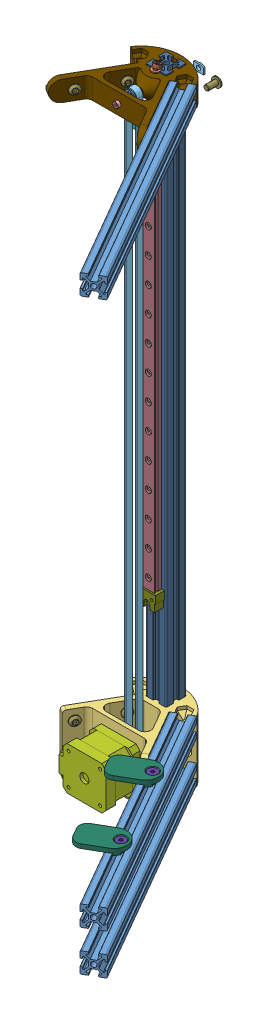
SolidWorks assembly Kossel ass-01, configuration Default. Lengths in mm.
Overall size (201.64 606.12 243.34).
97 component instances, 23 part files, 0 mates.
Components (placement in the parent):
- F623ZZ-1: F623ZZ [Default] at (0 -11 32.1273) x (-0.566355 0.824161 0) z (-0.824161 -0.566355 0) size (11.5 4 11.5)
- m3 t-slot-1: m3 t-slot [Default] at (0 -155.5 6.8) size (10 5 2.2)
- M3x8 socket screw-1: M3x8 socket screw [Default] at (0 -330.5 5) x (1 0 0) z (0 -1 0) size (5.6 10.9 5.6)
- m4 nut-1: m4 nut [Default] at (0 -16.4689 14.8541) x (0.866025 -0.154508 -0.475528) z (0.5 0.267617 0.823639) size (8.08 3 7)
- m5 t-slot-1: m5 t-slot [Default] at (41.8929 -590 51.6366) x (0 1 0) z (-0.866025 0 0.5) size (10 7 2.5)
- OMRON-SS-1: OMRON-SS [Default] at (-4.75 -39.5 22.2) x (-1 0 0) z (0 0 1) size (19.8 15.06 6.4)
- m3 t-slot-2: m3 t-slot [Default] at (0 -380.5 6.8) size (10 5 2.2)
- m3 t-slot-3: m3 t-slot [Default] at (0 -205.5 6.8) size (10 5 2.2)
- M3x8 socket screw-2: M3x8 socket screw [Default] at (0 -405.5 5) x (1 0 0) z (0 -1 0) size (5.6 10.9 5.6)
- m5 t-slot-2: m5 t-slot [Default] at (41.8929 -11 51.6367) x (0 1 0) z (-0.866025 0 0.5) size (10 7 2.5)
- m5 t-slot-3: m5 t-slot [Default] at (22.8929 -590 18.7277) x (0 -1 0) z (-0.866025 0 0.5) size (10 7 2.5)
- MP1872-Stepper_Motor_NEMA17-1: MP1872-Stepper_Motor_NEMA17 [Default] at (0.2889 -570 63.8273) x (0 1 0) z (-1 0 0) size (42.3 53.75 48.3)
- m3 nut-1: m3 nut [Default] at (0 -11 26.1273) size (5.77 5 2)
- Kossel-parts001-1: Kossel-parts001 [Default] at (0.2889 -570 36.5273) x (-0.148937 0.988847 0) z (0 0 1) size (14.7 14.7 12)
- m3 t-slot-4: m3 t-slot [Default] at (0 -405.5 6.8) size (10 5 2.2)
- M3x8 socket screw-3: M3x8 socket screw [Default] at (0 -255.5 5) x (1 0 0) z (0 -1 0) size (5.6 10.9 5.6)
- m5 t-slot-4: m5 t-slot [Default] at (22.8929 -11 18.7277) x (0 -1 0) z (-0.866025 0 0.5) size (10 7 2.5)
- m5 t-slot-5: m5 t-slot [Default] at (-41.8929 -590 51.6366) x (0 1 0) z (0.866025 0 0.5) size (10 7 2.5)
- 20x20x600-1: 20x20x600 [Default] x (-1 0 0) z (0 0 1) size (20 600 20)
- m4x20 socket screw-1: m4x20 socket screw [Default] at (0 -18.1808 15.4104) x (-0.866088 -0.154475 -0.475425) z (0.499892 -0.267636 -0.823699) size (7 24 7)
- F623ZZ-2: F623ZZ [Default] at (0 -11 32.1273) x (1 0 0) z (0 -1 0) size (11.5 4 11.5)
- m3 t-slot-5: m3 t-slot [Default] at (0 -330.5 6.8) size (10 5 2.2)
- M3x8 socket screw-4: M3x8 socket screw [Default] at (0 -130.5 5) x (1 0 0) z (0 -1 0) size (5.6 10.9 5.6)
- m5 t-slot-6: m5 t-slot [Default] at (-22.8929 -550 18.7277) x (0 -1 0) z (0.866025 0 0.5) size (10 7 2.5)
- m5 t-slot-7: m5 t-slot [Default] at (41.8929 -550 51.6366) x (0 1 0) z (-0.866025 0 0.5) size (10 7 2.5)
- m5 t-slot-8: m5 t-slot [Default] at (104.3002 -542 148.7294) x (0.866025 0 -0.5) z (0 -1 0) size (10 7 2.5)
- m3 t-slot-6: m3 t-slot [Default] at (0 -355.5 6.8) size (10 5 2.2)
- m5 t-slot-9: m5 t-slot [Default] at (-22.8929 -590 18.7277) x (0 -1 0) z (0.866025 0 0.5) size (10 7 2.5)
- m5x10 button screw-1: m5x10 button screw [Default] at (-42.7585 -11 51.1369) x (0.1551 -0.950671 -0.268642) z (-0.475336 -0.310201 0.823305) size (9.3 12.55 9.3)
- HI_r_SSEBLT13-396-1: HI_r_SSEBLT13-396 [Default] at (0 -45 10) x (1 0 0) z (0 -1 0) size (12 7.5 396)
- m3 t-slot-7: m3 t-slot [Default] at (0 -305.5 6.8) size (10 5 2.2)
- m3 t-slot-8: m3 t-slot [Default] at (0 -55.5 6.8) size (10 5 2.2)
- m5 t-slot-10: m5 t-slot [Default] at (61.6002 -542 74.7708) x (-0.866025 0 0.5) z (0 -1 0) size (10 7 2.5)
- m4x10 socket screw-1: m4x10 socket screw [Default] at (15.7889 -554.5 53.0773) x (0.60127 0.799046 0) z (-0.799046 0.60127 0) size (7 14 7)
- m5 t-slot-11: m5 t-slot [Default] at (-41.8929 -550 51.6366) x (0 -1 0) z (0.866025 0 0.5) size (10 7 2.5)
- m5x10 button screw-2: m5x10 button screw [Default] at (-23.7585 -11 18.2279) x (-0.482212 -0.264357 0.835216) z (-0.132178 0.964425 0.22894) size (9.3 12.55 9.3)
- m3 t-slot-9: m3 t-slot [Default] at (0 -280.5 6.8) size (10 5 2.2)
- M3x8 socket screw-5: M3x8 socket screw [Default] at (0 -205.5 5) x (1 0 0) z (0 -1 0) size (5.6 10.9 5.6)
- M3x8 socket screw-6: M3x8 socket screw [Default] at (0 -80.5 5) x (-0.999964 0.008516 0) z (0.008516 0.999964 0) size (5.6 10.9 5.6)
- glass_tab sw-1: glass_tab sw [Default] at (61.6002 -536 74.7708) x (-0.5 0 -0.866025) z (0 1 0) size (25.4 40.9 6)
- m5 t-slot-12: m5 t-slot [Default] at (22.8929 -550 18.7277) x (0 -1 0) z (-0.866025 0 0.5) size (10 7 2.5)
- m5x10 button screw-3: m5x10 button screw [Default] at (42.7585 -11 51.1369) x (-0.442414 -0.465918 -0.766284) z (-0.232959 0.884828 -0.403497) size (9.3 12.55 9.3)
- m3 t-slot-10: m3 t-slot [Default] at (0 -255.5 6.8) size (10 5 2.2)
- M3x8 socket screw-7: M3x8 socket screw [Default] at (0 -105.5 5) x (1 0 0) z (0 -1 0) size (5.6 10.9 5.6)
- M3x8 socket screw-8: M3x8 socket screw [Default] at (0 -155.5 5) x (1 0 0) z (0 -1 0) size (5.6 10.9 5.6)
- M3x8 socket screw-9: M3x8 socket screw [Default] at (0 -380.5 5) x (0.292877 0.95615 0) z (0.95615 -0.292877 0) size (5.6 10.9 5.6)
- m5 t-slot-13: m5 t-slot [Default] at (11.3303 -8.8222 -20.6644) x (-1 0 0) z (0 0 -1) size (10 7 2.5)
- m5x10 button screw-4: m5x10 button screw [Default] at (23.7585 -11 18.2279) x (-0.078334 0.987651 -0.135679) z (0.493826 0.156669 0.855331) size (9.3 12.55 9.3)
- m3 t-slot-11: m3 t-slot [Default] at (0 -180.5 6.8) size (10 5 2.2)
- M3x8 socket screw-10: M3x8 socket screw [Default] at (0 -451.5 6) x (1 0 0) z (0 -1 0) size (5.6 10.9 5.6)
- endstop sw-1: endstop sw [Default] at (0 -441 19) x (-1 0 0) z (0 0 1) size (17 15 11)
- m4x10 socket screw-2: m4x10 socket screw [Default] at (-15.2111 -554.5 53.0773) x (-0.923728 -0.383049 0) z (0.383049 -0.923728 0) size (7 14 7)
- m5x10 button screw-5: m5x10 button screw [Default] at (30.073 -11 -9.3275) x (0.79504 -0.606557 0) z (0.606557 0.79504 0) size (9.3 12.55 9.3)
- m5x10 button screw-6: m5x10 button screw [Default] at (42.7585 -590 51.1369) x (0.447252 -0.447062 0.774662) z (-0.223531 -0.894503 -0.387167) size (9.3 12.55 9.3)
- M3x8 socket screw-11: M3x8 socket screw [Default] at (0 -355.5 5) x (0.606296 -0.795239 0) z (-0.795239 -0.606296 0) size (5.6 10.9 5.6)
- M5x10 Socket Flat screw-1: M5x10 Socket Flat screw [Default] at (61.6002 -546.6 74.7708) size (9.52 10 9.52)
- m4x10 socket screw-3: m4x10 socket screw [Default] at (-15.2111 -585.5 53.0773) x (1 0 0) z (0 1 0) size (7 14 7)
- m5x10 button screw-7: m5x10 button screw [Default] at (0 -550 -4.5) x (-0.959087 0.28311 0) z (-0.28311 -0.959087 0) size (9.3 12.55 9.3)
- m5x10 button screw-8: m5x10 button screw [Default] at (23.7585 -550 18.2279) x (0.091381 -0.983157 0.158276) z (-0.491579 -0.182762 -0.851439) size (9.3 12.55 9.3)
- frame_top 2020sw-1: frame_top 2020sw [Default] at (0 -11 3.0773) x (-1 0 0) z (0 1 0) size (98.34 87.53 20.11)
- M3x8 socket screw-12: M3x8 socket screw [Default] at (0 -280.5 5) x (1 0 0) z (0 -1 0) size (5.6 10.9 5.6)
- m5x10 button screw-9: m5x10 button screw [Default] at (0 -580 -4.5) x (1 0 0) z (0 1 0) size (9.3 12.55 9.3)
- m5x10 button screw-10: m5x10 button screw [Default] at (23.7585 -590 18.2279) x (0.25 0.866025 0.433013) z (0.433013 -0.5 0.75) size (9.3 12.55 9.3)
- 20x20x240-1: 20x20x240 [Default] at (143.8163 -550 215.1731) x (0.866025 0 -0.5) z (0 1 0) size (20 240 20)
- endstop sw-2: endstop sw [Default] at (0 -45 19) size (17 15 11)
- m5 t-slot-14: m5 t-slot [Default] at (0 -550 -6.5) x (-1 0 0) z (0 0 -1) size (10 7 2.5)
- m5x10 button screw-11: m5x10 button screw [Default] at (42.7585 -550 51.1369) x (0.116422 0.972514 0.201649) z (0.486257 -0.232844 0.842222) size (9.3 12.55 9.3)
- m5x10 button screw-12: m5x10 button screw [Default] at (-23.7589 -550 18.2277) x (0.499479 -0.045654 -0.865122) z (-0.022827 -0.998957 0.039538) size (9.3 12.55 9.3)
- 20x20x240-2: 20x20x240 [Default] at (143.8163 -590 215.1731) x (0.866025 0 -0.5) z (0 1 0) size (20 240 20)
- m3 nut-2: m3 nut [Default] at (0 -11 36.1273) size (5.77 5 2)
- m3 t-slot-12: m3 t-slot [Default] at (0 -230.5 6.8) size (10 5 2.2)
- m4x10 socket screw-4: m4x10 socket screw [Default] at (15.7889 -585.5 53.0773) x (1 0 0) z (0 1 0) size (7 14 7)
- m5 t-slot-15: m5 t-slot [Default] at (0 -580 -6.5) x (-1 0 0) z (0 0 -1) size (10 7 2.5)
- m5x10 button screw-13: m5x10 button screw [Default] at (-23.7589 -590 18.2277) x (0.071086 -0.989842 -0.123125) z (-0.494921 -0.142172 0.857228) size (9.3 12.55 9.3)
- 20x20x240-3: 20x20x240 [Default] at (23.8163 -11 7.327) x (0.866025 0 -0.5) z (0 -1 0) size (20 240 20)
- glass_tab sw-2: glass_tab sw [Default] at (104.3002 -536 148.7294) x (-0.5 0 -0.866025) z (0 1 0) size (25.4 40.9 6)
- m3 t-slot-13: m3 t-slot [Default] at (0 -130.5 6.8) size (10 5 2.2)
- M3x8 socket screw-13: M3x8 socket screw [Default] at (0 -180.5 5) x (1 0 0) z (0 -1 0) size (5.6 10.9 5.6)
- M3x8 socket screw-14: M3x8 socket screw [Default] at (0 -305.5 5) x (1 0 0) z (0 -1 0) size (5.6 10.9 5.6)
- Gasket id4.2-1: Gasket id4.2 [Default] at (0 -1 10.1498) x (-0.468828 0 -0.883289) z (0.883289 0 -0.468828) size (8 1 8)
- m5x10 button screw-14: m5x10 button screw [Default] at (-42.7589 -550 51.1366) x (0.25 -0.866025 -0.433013) z (-0.433013 -0.5 0.75) size (9.3 12.55 9.3)
- M5x10 Socket Flat screw-2: M5x10 Socket Flat screw [Default] at (104.3002 -546.6 148.7294) size (9.52 10 9.52)
- m3 t-slot-14: m3 t-slot [Default] at (0 -451.5 6.8) size (10 5 2.2)
- m3 t-slot-15: m3 t-slot [Default] at (0 -34.5 6.8) size (10 5 2.2)
- m5x10 button screw-15: m5x10 button screw [Default] at (-42.7589 -590 51.1366) x (0.007392 -0.999891 -0.012803) z (-0.499945 -0.014783 0.865931) size (9.3 12.55 9.3)
- frame_motor 2020sw-1: frame_motor 2020sw [Default] at (0 -600 29) x (1 0 0) z (0 -1 0) size (88.34 78.87 60)
- m3 t-slot-16: m3 t-slot [Default] at (0 -430.5 6.8) size (10 5 2.2)
- m3 t-slot-17: m3 t-slot [Default] at (0 -80.5 6.8) size (10 5 2.2)
- M3x8 socket screw-15: M3x8 socket screw [Default] at (0 -230.5 5) x (1 0 0) z (0 -1 0) size (5.6 10.9 5.6)
- M3x8 socket screw-16: M3x8 socket screw [Default] at (0 -34.5 6) x (1 0 0) z (0 -1 0) size (5.6 10.9 5.6)
- m5 t-slot-16: m5 t-slot [Default] at (-22.8929 -11 18.7277) x (0 1 0) z (0.866025 0 0.5) size (10 7 2.5)
- m3x30 socket screw-1: m3x30 socket screw [Default] at (0 -11 17.0773) x (1 0 0) z (0 -1 0) size (5.5 33 5.5)
- 1164mm GT2 belt-1: 1164mm GT2 belt [Default] at (0.2889 -10 29.1273) x (-1 0 0) z (0 0 1) size (12 572 6)
- m3 t-slot-18: m3 t-slot [Default] at (0 -105.5 6.8) size (10 5 2.2)
- M3x8 socket screw-17: M3x8 socket screw [Default] at (0 -430.5 5) x (1 0 0) z (0 -1 0) size (5.6 10.9 5.6)
- M3x8 socket screw-18: M3x8 socket screw [Default] at (0 -55.5 5) x (-0.995135 0.098523 0) z (0.098523 0.995135 0) size (5.6 10.9 5.6)
- m5 t-slot-17: m5 t-slot [Default] at (-41.8929 -11 51.6367) x (0 1 0) z (0.866025 0 0.5) size (10 7 2.5)
